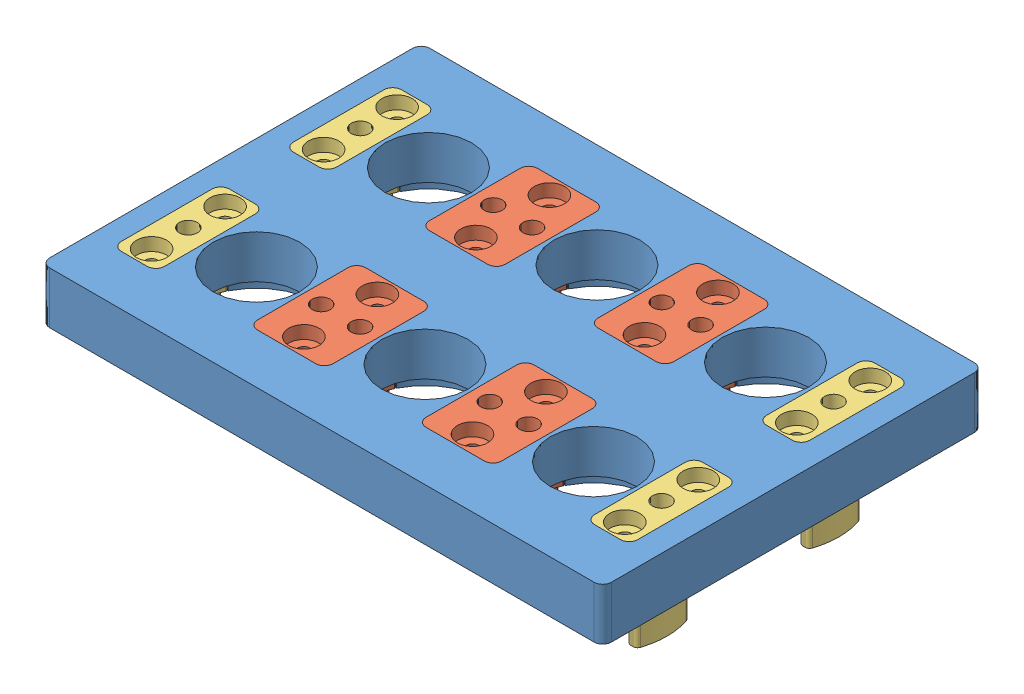
SolidWorks assembly Ass - Manifold V2.1, configuration Default. Lengths in mm.
Overall size (130 26.5 88).
9 component instances, 3 part files, 24 mates.
Components (placement in the parent):
- Manifold V2.1-1: Manifold V2.1 [Default] at origin size (130 14.5 88)
- Manifold V2.1 – insert dvojni-1: Manifold V2.1 – insert dvojni [Default] at origin size (17.5 26.5 25)
- Manifold V2.1 – insert enojni-1: Manifold V2.1 – insert enojni [Default] at origin size (10 26.5 25)
- Manifold V2.1 – insert dvojni-2: Manifold V2.1 – insert dvojni [Default] at (-39 0 0) size (17.5 26.5 25)
- Manifold V2.1 – insert dvojni-3: Manifold V2.1 – insert dvojni [Default] at (-39 0 -39.8) size (17.5 26.5 25)
- Manifold V2.1 – insert dvojni-4: Manifold V2.1 – insert dvojni [Default] at (0 0 -39.8) size (17.5 26.5 25)
- Manifold V2.1 – insert enojni-2: Manifold V2.1 – insert enojni [Default] at (0 0 -39.8) size (10 26.5 25)
- Manifold V2.1 – insert enojni-3: Manifold V2.1 – insert enojni [Default] at (123 0 121.3) x (-1 0 0) z (0 0 -1) size (10 26.5 25)
- Manifold V2.1 – insert enojni-4: Manifold V2.1 – insert enojni [Default] at (123 0 81.5) x (-1 0 0) z (0 0 -1) size (10 26.5 25)
Mates (geometry in assembly coordinates):
- Coincident1: coincident anti-aligned: plane of Manifold V2.1-1 through (72.25 -2 73.15) normal (0 0 -1); plane of Manifold V2.1 – insert dvojni-1 through (72.25 -23.5 73.15) normal (0 0 1)
- Coincident2: coincident anti-aligned: plane of Manifold V2.1-1 through (72.25 -2 48.15) normal (1 0 0); plane of Manifold V2.1 – insert dvojni-1 through (72.25 -23.5 48.15) normal (-1 0 0)
- Coincident3: coincident aligned: plane of Manifold V2.1-1 through (124.75 3 82.75) normal (0 1 0); plane of Manifold V2.1 – insert dvojni-1 through (124.75 3 82.75) normal (0 1 0)
- Coincident4: coincident anti-aligned: plane of Manifold V2.1-1 through (111.25 -2 48.15) normal (0 0 1); plane of Manifold V2.1 – insert enojni-1 through (111.25 -23.5 48.15) normal (0 0 -1)
- Coincident5: coincident anti-aligned: plane of Manifold V2.1-1 through (111.25 -2 48.15) normal (1 0 0); plane of Manifold V2.1 – insert enojni-1 through (111.25 -23.5 48.15) normal (-1 0 0)
- Coincident6: coincident aligned: plane of Manifold V2.1-1 through (124.75 3 82.75) normal (0 1 0); plane of Manifold V2.1 – insert enojni-1 through (124.75 3 82.75) normal (0 1 0)
- Coincident7: coincident anti-aligned: plane of Manifold V2.1-1 through (50.75 -2 8.35) normal (0 0 1); plane of Manifold V2.1 – insert dvojni-3 through (33.25 -23.5 8.35) normal (0 0 -1)
- Coincident8: coincident anti-aligned: plane of Manifold V2.1-1 through (33.25 -2 33.35) normal (1 0 0); plane of Manifold V2.1 – insert dvojni-3 through (33.25 -23.5 8.35) normal (-1 0 0)
- Coincident9: coincident aligned: plane of Manifold V2.1-1 through (124.75 3 82.75) normal (0 1 0); plane of Manifold V2.1 – insert dvojni-3 through (85.75 3 42.95) normal (0 1 0)
- Coincident10: coincident anti-aligned: plane of Manifold V2.1-1 through (0 -2 0) normal (0 1 0); plane of Manifold V2.1 – insert dvojni-2 through (-39 -2 0) normal (0 -1 0)
- Coincident11: coincident anti-aligned: plane of Manifold V2.1-1 through (50.75 -2 48.15) normal (0 0 1); plane of Manifold V2.1 – insert dvojni-2 through (33.25 -23.5 48.15) normal (0 0 -1)
- Coincident12: coincident anti-aligned: plane of Manifold V2.1-1 through (50.75 -2 48.15) normal (-1 0 0); plane of Manifold V2.1 – insert dvojni-2 through (50.75 -23.5 48.15) normal (1 0 0)
- Coincident13: coincident aligned: plane of Manifold V2.1-1 through (124.75 3 82.75) normal (0 1 0); plane of Manifold V2.1 – insert dvojni-4 through (124.75 3 42.95) normal (0 1 0)
- Coincident14: coincident anti-aligned: plane of Manifold V2.1-1 through (72.25 -2 33.35) normal (1 0 0); plane of Manifold V2.1 – insert dvojni-4 through (72.25 -23.5 8.35) normal (-1 0 0)
- Coincident15: coincident anti-aligned: plane of Manifold V2.1-1 through (72.25 -2 8.35) normal (0 0 1); plane of Manifold V2.1 – insert dvojni-4 through (72.25 -23.5 8.35) normal (0 0 -1)
- Coincident16: coincident anti-aligned: plane of Manifold V2.1-1 through (121.25 -2 33.35) normal (-1 0 0); plane of Manifold V2.1 – insert enojni-2 through (121.25 -23.5 8.35) normal (1 0 0)
- Coincident17: coincident anti-aligned: plane of Manifold V2.1-1 through (111.25 -2 33.35) normal (0 0 -1); plane of Manifold V2.1 – insert enojni-2 through (111.25 -23.5 33.35) normal (0 0 1)
- Coincident18: coincident aligned: plane of Manifold V2.1-1 through (124.75 3 82.75) normal (0 1 0); plane of Manifold V2.1 – insert enojni-2 through (124.75 3 42.95) normal (0 1 0)
- Coincident19: coincident aligned: plane of Manifold V2.1-1 through (124.75 3 82.75) normal (0 1 0); plane of Manifold V2.1 – insert enojni-4 through (-1.75 3 -1.25) normal (0 1 0)
- Coincident20: coincident anti-aligned: plane of Manifold V2.1-1 through (11.75 -2 8.35) normal (0 0 1); plane of Manifold V2.1 – insert enojni-4 through (11.75 -23.5 8.35) normal (0 0 -1)
- Coincident21: coincident anti-aligned: plane of Manifold V2.1-1 through (11.75 -2 33.35) normal (-1 0 0); plane of Manifold V2.1 – insert enojni-4 through (11.75 -23.5 33.35) normal (1 0 0)
- Coincident22: coincident anti-aligned: plane of Manifold V2.1-1 through (11.75 -2 48.15) normal (0 0 1); plane of Manifold V2.1 – insert enojni-3 through (11.75 -23.5 48.15) normal (0 0 -1)
- Coincident23: coincident anti-aligned: plane of Manifold V2.1-1 through (1.75 -2 48.15) normal (1 0 0); plane of Manifold V2.1 – insert enojni-3 through (1.75 -23.5 73.15) normal (-1 0 0)
- Coincident24: coincident aligned: plane of Manifold V2.1-1 through (124.75 3 82.75) normal (0 1 0); plane of Manifold V2.1 – insert enojni-3 through (-1.75 3 38.55) normal (0 1 0)
